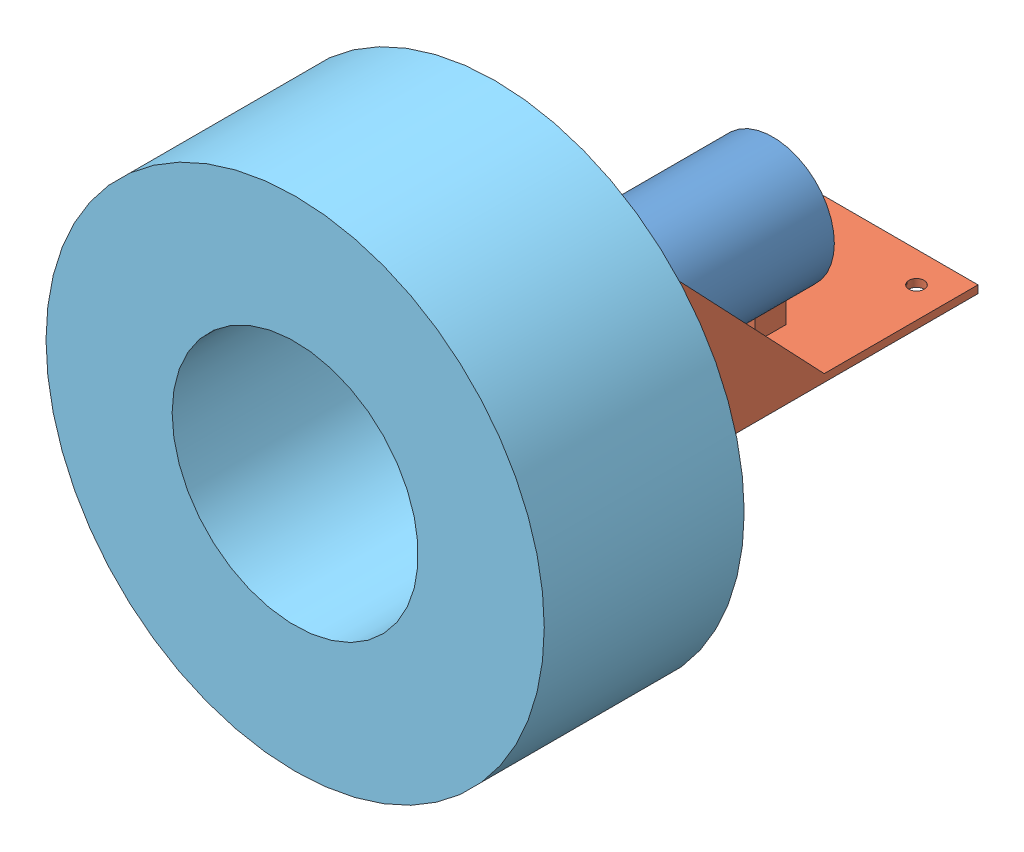
SolidWorks assembly EA1, configuration Default. Lengths in mm.
Overall size (411.48 411.48 487.68).
29 component instances, 8 part files, 38 mates.
Components (placement in the parent):
- EB1-1: EB1 [Default] at (60.2077 126.1588 196.7963) size (101.6 101.6 238.25)
- EP1-1: EP1 [Default] at (60.2077 56.3088 69.7963) x (0 0 1) z (-1 0 0) size (254 133.35 152.4)
- EA2-1: EA2 [Default] at (45.9187 58.6487 138.5565) size (411.48 411.48 213.36)
  - EP2-1: EP2 [Default] at (14.289 67.5101 114.1198) size (127 127 48.26)
  - hex bolt_ai-1: hex bolt_ai [HBOLT 0.4375-20x1.375x1.125-N] at (-36.511 67.5101 106.0934) x (0 0 1) z (-0.866025 -0.5 0) size (42.95 18.33 15.88)
  - hex bolt_ai-2: hex bolt_ai [HBOLT 0.4375-20x1.375x1.125-N] at (14.289 118.3101 106.0934) x (0 0 1) z (0 -1 0) size (42.95 18.33 15.88)
  - hex bolt_ai-3: hex bolt_ai [HBOLT 0.4375-20x1.375x1.125-N] at (14.289 16.7101 106.0934) x (0 0 1) z (-0.866025 0.5 0) size (42.95 18.33 15.88)
  - hex bolt_ai-4: hex bolt_ai [HBOLT 0.4375-20x1.375x1.125-N] at (65.089 67.5101 106.0934) x (0 0 1) z (-0.866025 0.5 0) size (42.95 18.33 15.88)
  - EB2-1: EB2 [Default] at (14.289 67.5101 129.9948) x (-1 0 0) z (0 0 -1) size (411.48 411.48 165.1)
  - flat washer type a wide_ai-1: flat washer type a wide_ai [Preferred Wide FW 0.4375] at (-36.511 67.5101 132.103) x (0 0 1) z (-0.923728 -0.383049 0) size (2.11 31.75 31.75)
  - flat washer type a wide_ai-2: flat washer type a wide_ai [Preferred Wide FW 0.4375] at (14.289 118.3101 132.103) x (0 0 1) z (1 0 0) size (2.11 31.75 31.75)
  - flat washer type a wide_ai-3: flat washer type a wide_ai [Preferred Wide FW 0.4375] at (14.289 16.7101 132.103) x (0 0 1) z (1 0 0) size (2.11 31.75 31.75)
  - flat washer type a wide_ai-4: flat washer type a wide_ai [Preferred Wide FW 0.4375] at (65.089 67.5101 132.103) x (0 0 1) z (1 0 0) size (2.11 31.75 31.75)
  - hex thick nut_ai-1: hex thick nut_ai [HTNUT 0.4375-14-D-N] at (14.289 16.7101 143.8632) x (0.055202 -0.998475 0) z (0 0 1) size (17.48 20.18 11.76)
  - hex thick nut_ai-2: hex thick nut_ai [HTNUT 0.4375-14-D-N] at (-36.511 67.5101 143.8632) x (0.547044 -0.837104 0) z (0 0 1) size (17.48 20.18 11.76)
  - hex thick nut_ai-3: hex thick nut_ai [HTNUT 0.4375-14-D-N] at (65.089 67.5101 143.8632) x (-0.982324 -0.18719 0) z (0 0 1) size (17.48 20.18 11.76)
  - hex thick nut_ai-4: hex thick nut_ai [HTNUT 0.4375-14-D-N] at (14.289 118.3101 143.8632) x (0.055202 -0.998475 0) z (0 0 1) size (17.48 20.18 11.76)
- hex bolt_ai-8: hex bolt_ai [HBOLT 0.3125-18x1.375x0.875-N] at (17.0277 169.3388 215.4653) x (0 0 -1) z (0 1 0) size (40.89 14.66 12.7)
- hex bolt_ai-9: hex bolt_ai [HBOLT 0.3125-18x1.375x0.875-N] at (103.3877 169.3388 215.4653) x (0 0 -1) z (0.866025 -0.5 0) size (40.89 14.66 12.7)
- hex bolt_ai-10: hex bolt_ai [HBOLT 0.3125-18x1.375x0.875-N] at (103.3877 82.9788 215.4653) x (0 0 -1) z (0.866025 0.5 0) size (40.89 14.66 12.7)
- hex bolt_ai-11: hex bolt_ai [HBOLT 0.3125-18x1.375x0.875-N] at (17.0277 82.9788 215.4653) x (0 0 -1) z (-0.866025 -0.5 0) size (40.89 14.66 12.7)
- flat washer type a narrow_ai-1: flat washer type a narrow_ai [Preferred Narrow FW 0.3125] at (17.0277 169.3388 190.4463) x (0 0 1) z (-1 0 0) size (1.65 17.48 17.48)
- flat washer type a narrow_ai-2: flat washer type a narrow_ai [Preferred Narrow FW 0.3125] at (103.3877 82.9788 190.4463) x (0 0 1) z (-1 0 0) size (1.65 17.48 17.48)
- flat washer type a narrow_ai-3: flat washer type a narrow_ai [Preferred Narrow FW 0.3125] at (17.0277 82.9788 188.7953) x (0 0 -1) z (1 0 0) size (1.65 17.48 17.48)
- flat washer type a narrow_ai-4: flat washer type a narrow_ai [Preferred Narrow FW 0.3125] at (103.3877 169.3388 188.7953) x (0 0 -1) z (0.923728 0.383049 0) size (1.65 17.48 17.48)
- hex thick nut_ai-1: hex thick nut_ai [HTNUT 0.3125-18-D-N] at (103.3877 169.3388 188.7953) x (0.866025 0.5 0) z (0 0 1) size (12.7 14.66 8.53)
- hex thick nut_ai-2: hex thick nut_ai [HTNUT 0.3125-18-D-N] at (17.0277 82.9788 180.2609) x (-0.866025 0.5 0) z (0 0 -1) size (12.7 14.66 8.53)
- hex thick nut_ai-3: hex thick nut_ai [HTNUT 0.3125-18-D-N] at (103.3877 82.9788 181.9119) x (-0.866025 -0.5 0) z (0 0 -1) size (12.7 14.66 8.53)
- hex thick nut_ai-4: hex thick nut_ai [HTNUT 0.3125-18-D-N] at (17.0277 169.3388 180.2609) x (-0.866025 -0.5 0) z (0 0 -1) size (12.7 14.66 8.53)
Mates (geometry in assembly coordinates):
- Concentric9: concentric: cylinder of EB1-1 through (60.2077 126.1588 36.0143) axis (0 0 1) radius 50.8; cylinder of EP1-1 through (60.2077 126.1588 190.4463) axis (0 0 1) radius 50.8
- Coincident13: coincident: cylinder of EB1-1 through (103.3877 169.3388 209.4963) axis (0 0 -1) radius 4.318; circle of EP1-1
- Coincident14: coincident: plane of EB1-1 through (60.2077 126.1588 196.7963) normal (0 0 -1); plane of EP1-1 through (136.4077 62.6588 196.7963) normal (0 0 1)
- Parallel1: parallel: line of EB1-1 through (60.2077 131.2226 252.6763) axis (1 0 0); line of EA2-1/EP2-1 through (57.8201 131.2226 217.1163) axis (1 0 0)
- Concentric10: concentric: cylinder of EB1-1 through (60.2077 126.1588 252.6763) axis (0 0 -1) radius 7.9375; cylinder of EA2-1/EP2-1 through (60.2077 126.1588 217.1163) axis (0 0 1) radius 7.9375
- Coincident16: coincident: plane of EB1-1 through (60.2077 126.1588 252.6763) normal (0 0 1); plane of EA2-1/EP2-1 through (60.2077 126.1588 252.6763) normal (0 0 -1)
- Concentric12: concentric: cylinder of EB1-1 through (103.3877 169.3388 209.4963) axis (0 0 -1) radius 4.318; cylinder of hex bolt_ai-9 through (103.3877 169.3388 215.4653) axis (0 0 1) radius 3.9688
- Coincident18: coincident: plane of EB1-1 through (60.2077 126.1588 209.4963) normal (0 0 1); plane of hex bolt_ai-9 through (107.0539 175.6888 209.4963) normal (0 0 -1)
- Parallel2: parallel: line of EB1-1 through (9.4077 75.3588 209.4963) axis (1 0 0); line of hex bolt_ai-9 through (107.0539 162.9888 209.4963) axis (-1 0 0)
- Concentric13: concentric: cylinder of hex bolt_ai-9 through (103.3877 169.3388 215.4653) axis (0 0 1) radius 3.9688; cylinder of flat washer type a narrow_ai-4 through (103.3877 169.3388 223.7203) axis (0 0 1) radius 4.3688
- Coincident20: coincident: plane of EP1-1 through (60.2077 56.3088 190.4463) normal (0 0 -1); plane of flat washer type a narrow_ai-4 through (100.0408 177.4099 190.4463) normal (0 0 1)
- Concentric14: concentric: cylinder of hex bolt_ai-9 through (103.3877 169.3388 215.4653) axis (0 0 1) radius 3.9688; cylinder of hex thick nut_ai-1 through (103.3877 169.3388 180.2609) axis (0 0 1) radius 3.2639
- Parallel3: parallel: line of EP1-1 through (136.4077 56.3088 -57.2037) axis (-1 0 0); plane of hex thick nut_ai-1 through (107.0539 175.6888 180.2609) normal (0 1 0)
- Coincident22: coincident: plane of flat washer type a narrow_ai-4 through (101.7143 173.3744 188.7953) normal (0 0 -1); plane of hex thick nut_ai-1 through (99.7216 175.6888 188.7953) normal (0 0 1)
- Concentric15: concentric: cylinder of EB1-1 through (17.0277 169.3388 209.4963) axis (0 0 -1) radius 4.318; cylinder of hex bolt_ai-8 through (17.0277 169.3388 215.4653) axis (0 0 1) radius 3.9688
- Coincident23: coincident: plane of EB1-1 through (60.2077 126.1588 209.4963) normal (0 0 1); plane of hex bolt_ai-8 through (9.6954 169.3388 209.4963) normal (0 0 -1)
- Parallel4: parallel: line of EP1-1 through (-15.9923 56.3088 196.7963) axis (1 0 0); plane of hex bolt_ai-8 through (13.3616 175.6888 209.4963) normal (0 1 0)
- Coincident25: coincident: plane of EP1-1 through (60.2077 56.3088 190.4463) normal (0 0 -1); plane of flat washer type a narrow_ai-1 through (17.0277 173.7076 190.4463) normal (0 0 1)
- Concentric16: concentric: cylinder of hex bolt_ai-8 through (17.0277 169.3388 215.4653) axis (0 0 1) radius 3.9688; cylinder of flat washer type a narrow_ai-1 through (17.0277 169.3388 155.5213) axis (0 0 -1) radius 4.3688
- Coincident26: coincident: plane of flat washer type a narrow_ai-1 through (17.0277 178.0764 188.7953) normal (0 0 -1); plane of hex thick nut_ai-4 through (13.3616 175.6888 188.7953) normal (0 0 1)
- Concentric17: concentric: cylinder of hex bolt_ai-8 through (17.0277 169.3388 215.4653) axis (0 0 1) radius 3.9688; cylinder of hex thick nut_ai-4 through (17.0277 169.3388 188.7953) axis (0 0 -1) radius 3.2639
- Parallel5: parallel: line of EP1-1 through (136.4077 56.3088 -57.2037) axis (-1 0 0); plane of hex thick nut_ai-4 through (13.3616 175.6888 188.7953) normal (0 1 0)
- Concentric18: concentric: cylinder of EB1-1 through (103.3877 82.9788 209.4963) axis (0 0 -1) radius 4.318; cylinder of hex bolt_ai-10 through (103.3877 82.9788 215.4653) axis (0 0 1) radius 3.9688
- Coincident28: coincident: plane of EB1-1 through (60.2077 126.1588 209.4963) normal (0 0 1); plane of hex bolt_ai-10 through (99.7216 89.3288 209.4963) normal (0 0 -1)
- Parallel6: parallel: line of EP1-1 through (-15.9923 56.3088 196.7963) axis (1 0 0); plane of hex bolt_ai-10 through (99.7216 89.3288 209.4963) normal (0 1 0)
- Coincident30: coincident: plane of EP1-1 through (60.2077 56.3088 190.4463) normal (0 0 -1); plane of flat washer type a narrow_ai-2 through (103.3877 87.3476 190.4463) normal (0 0 1)
- Concentric19: concentric: cylinder of hex bolt_ai-10 through (103.3877 82.9788 215.4653) axis (0 0 1) radius 3.9688; cylinder of flat washer type a narrow_ai-2 through (103.3877 82.9788 155.5213) axis (0 0 -1) radius 4.3688
- Coincident31: coincident: plane of EP1-1 through (60.2077 56.3088 190.4463) normal (0 0 -1); plane of hex thick nut_ai-3 through (99.7216 89.3288 190.4463) normal (0 0 1)
- Concentric20: concentric: cylinder of hex bolt_ai-10 through (103.3877 82.9788 215.4653) axis (0 0 1) radius 3.9688; cylinder of hex thick nut_ai-3 through (103.3877 82.9788 190.4463) axis (0 0 -1) radius 3.2639
- Parallel7: parallel: plane of EP1-1 through (60.2077 62.6588 69.7963) normal (0 1 0); plane of hex thick nut_ai-3 through (99.7216 89.3288 190.4463) normal (0 1 0)
- Concentric21: concentric: cylinder of EP1-1 through (17.0277 82.9788 190.4463) axis (0 0 1) radius 4.318; cylinder of hex bolt_ai-11 through (17.0277 82.9788 215.4653) axis (0 0 1) radius 3.9688
- Coincident33: coincident: plane of EB1-1 through (60.2077 126.1588 209.4963) normal (0 0 1); plane of hex bolt_ai-11 through (20.6939 76.6288 209.4963) normal (0 0 -1)
- Parallel8: parallel: line of EP1-1 through (-15.9923 56.3088 196.7963) axis (1 0 0); plane of hex bolt_ai-11 through (20.6939 89.3288 209.4963) normal (0 1 0)
- Coincident35: coincident: plane of EP1-1 through (60.2077 56.3088 190.4463) normal (0 0 -1); plane of flat washer type a narrow_ai-3 through (17.0277 91.7164 190.4463) normal (0 0 1)
- Concentric22: concentric: cylinder of hex bolt_ai-11 through (17.0277 82.9788 215.4653) axis (0 0 1) radius 3.9688; cylinder of flat washer type a narrow_ai-3 through (17.0277 82.9788 223.7203) axis (0 0 1) radius 4.3688
- Coincident36: coincident: plane of flat washer type a narrow_ai-3 through (17.0277 87.3476 188.7953) normal (0 0 -1); plane of hex thick nut_ai-2 through (20.6939 89.3288 188.7953) normal (0 0 1)
- Concentric23: concentric: cylinder of hex bolt_ai-11 through (17.0277 82.9788 215.4653) axis (0 0 1) radius 3.9688; cylinder of hex thick nut_ai-2 through (17.0277 82.9788 188.7953) axis (0 0 -1) radius 3.2639
- Parallel9: parallel: plane of EP1-1 through (60.2077 62.6588 69.7963) normal (0 1 0); plane of hex thick nut_ai-2 through (13.3616 89.3288 188.7953) normal (0 1 0)
